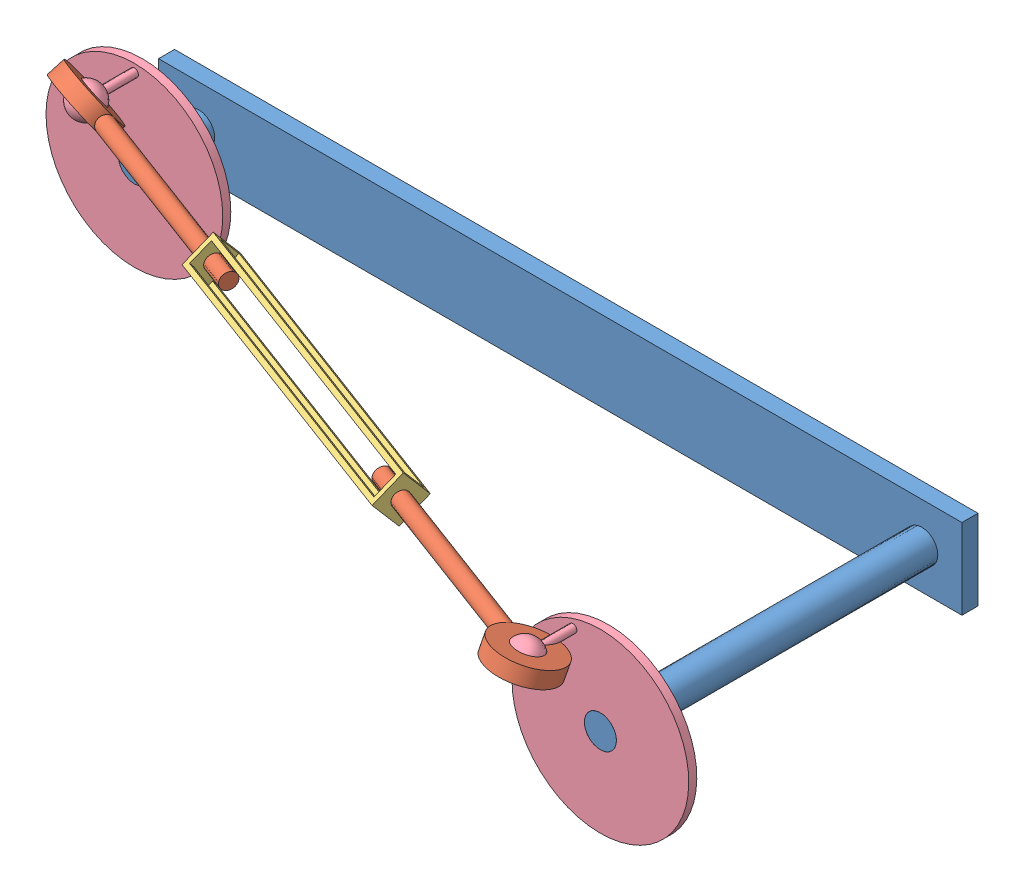
SolidWorks assembly Q8, configuration Default. Lengths in mm.
Overall size (575.49 160.62 266.19).
6 component instances, 4 part files, 11 mates.
Components (placement in the parent):
- Base-1: Base [Default] at (-21.8404 220.2936 267.503) size (500 50 210)
- Connecting_Rod-1: Connecting_Rod [Default] at (3.1596 295.2936 347.503) x (0.937963 -0.006533 0.346672) z (0.285319 0.582662 -0.760985) size (170 40 10)
- Connector_Block-1: Connector_Block [Default] at (126.1065 280.326 393.9826) x (0.937963 -0.006533 0.346672) z (-0.223055 0.754107 0.617713) size (200 20 20)
- Wheel_component-1: Wheel_component [Default] at (3.1596 295.2936 347.503) x (0 0 -1) z (1 0 0) size (45 142.07 110)
- Wheel_component-2: Wheel_component [Default] at (436.0586 292.2782 507.503) x (0 0 -1) z (0.939693 0.34202 0) size (45 142.07 110)
- Connecting_Rod-2: Connecting_Rod [Default] at (436.0586 292.2782 507.503) x (-0.937963 0.006533 -0.346672) z (-0.120368 -0.943779 0.307883) size (170 40 10)
Mates (geometry in assembly coordinates):
- Concentric1: concentric anti-aligned: cylinder of Base-1 through (3.1596 245.2936 317.503) axis (0 0 -1) radius 10; cylinder of Wheel_component-1 through (3.1596 245.2936 312.503) axis (0 0 1) radius 10
- Coincident1: coincident aligned: plane of Base-1 through (228.1596 -145.6963 317.503) normal (0 0 1); plane of Wheel_component-1 through (3.1596 245.2936 317.503) normal (0 0 1)
- Concentric2: concentric anti-aligned: cylinder of Base-1 through (453.1596 245.2936 477.503) axis (0 0 -1) radius 10; cylinder of Wheel_component-2 through (453.1596 245.2936 472.503) axis (0 0 1) radius 10
- Coincident2: coincident aligned: plane of Base-1 through (228.1596 -145.6963 477.503) normal (0 0 1); plane of Wheel_component-2 through (453.1596 245.2936 477.503) normal (0 0 1)
- Concentric3: concentric: sphere of Connecting_Rod-1; sphere of Wheel_component-1
- Concentric4: concentric: sphere of Wheel_component-2; sphere of Connecting_Rod-2
- Concentric5: concentric anti-aligned: cylinder of Connecting_Rod-1 through (3.1596 295.2936 347.503) axis (-0.938398 0.005285 -0.345516) radius 5; cylinder of Connector_Block-1 through (128.0374 294.5904 393.4827) axis (0.938398 -0.005285 0.345516) radius 5
- Parallel2: parallel anti-aligned: line of Base-1 through (-21.8404 270.2936 277.503) axis (0 -1 0); line of Wheel_component-1 through (3.1596 245.2936 317.503) axis (0 1 0)
- Angle1: planar angle = 0.349066 rad aligned: line of Wheel_component-2 through (453.1596 245.2936 477.503) axis (-0.34202 0.939693 0); line of Base-1 through (478.1596 220.2936 277.503) axis (0 1 0)
- Concentric8: concentric aligned: cylinder of Connector_Block-1 through (128.0374 294.5904 393.4827) axis (0.938398 -0.005285 0.345516) radius 5; cylinder of Connecting_Rod-2 through (437.7087 292.8464 507.503) axis (0.938398 -0.005285 0.345516) radius 5
- Distance1: distance = 20 mm anti-aligned: plane of Connecting_Rod-2 through (295.3641 293.2582 455.5021) normal (-0.937963 0.006533 -0.346672); plane of Connector_Block-1 through (309.2382 294.1015 475.6714) normal (0.937963 -0.006533 0.346672)
